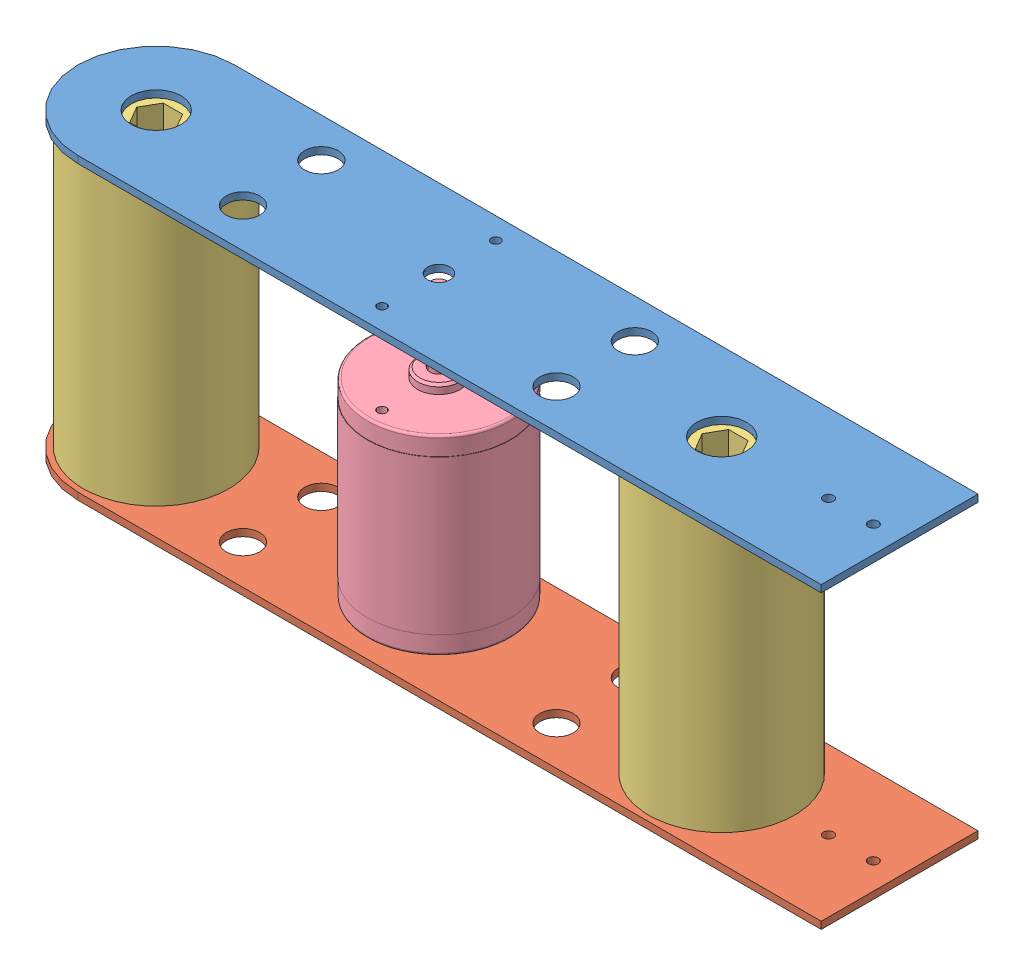
SolidWorks assembly pneumaticShaft, configuration Default. Lengths in mm.
Overall size (407.92 133.35 70).
5 component instances, 4 part files, 9 mates.
Components (placement in the parent):
- topPlate-1: topPlate [Default] at (83.6152 147.0048 280.3565) size (407.92 3.17 70)
- bottomPlate-1: bottomPlate [Default] at (83.6152 16.8298 280.3565) size (407.92 3.17 70)
- shaft-1: shaft [Default] at (209.8734 20.0048 280.3565) x (0.999976 0 -0.006968) z (0.006968 0 0.999976) size (65 127 65)
- shaft-2: shaft [Default] at (-42.643 20.0048 280.3565) size (65 127 65)
- Mini CIM-1: Mini CIM [Default] at (83.6152 110.0064 280.3565) x (0 -1 0) z (1 0 0) size (125.82 64.01 64.01)
Mates (geometry in assembly coordinates):
- Concentric2: concentric aligned: cylinder of topPlate-1 through (-42.643 150.1798 280.3565) axis (0 -1 0) radius 11.15; cylinder of shaft-2 through (-42.643 147.0048 280.3565) axis (0 -1 0) radius 32.5
- Coincident2: coincident anti-aligned: plane of topPlate-1 through (83.6152 147.0048 280.3565) normal (0 -1 0); plane of shaft-2 through (-42.643 147.0048 280.3565) normal (0 1 0)
- Coincident3: coincident anti-aligned: plane of bottomPlate-1 through (83.6152 20.0048 280.3565) normal (0 1 0); plane of shaft-2 through (-42.643 20.0048 280.3565) normal (0 -1 0)
- Concentric3: concentric aligned: cylinder of bottomPlate-1 through (-42.643 20.0048 280.3565) axis (0 -1 0) radius 11.15; cylinder of shaft-2 through (-42.643 147.0048 280.3565) axis (0 -1 0) radius 32.5
- Coincident6: coincident anti-aligned: plane of bottomPlate-1 through (83.6152 20.0048 280.3565) normal (0 1 0); plane of shaft-1 through (209.8734 20.0048 280.3565) normal (0 -1 0)
- Concentric5: concentric anti-aligned: circle of bottomPlate-1; cylinder of shaft-1 through (209.8734 147.0048 280.3565) axis (0 -1 0) radius 32.5
- Concentric6: concentric aligned: cylinder of topPlate-1 through (209.8734 150.1798 280.3565) axis (0 -1 0) radius 11.15; cylinder of shaft-1 through (209.8734 147.0048 280.3565) axis (0 -1 0) radius 32.5
- Concentric7: concentric aligned: circle of bottomPlate-1; circle of Mini CIM-1
- Concentric8: concentric anti-aligned: circle of topPlate-1; circle of Mini CIM-1
